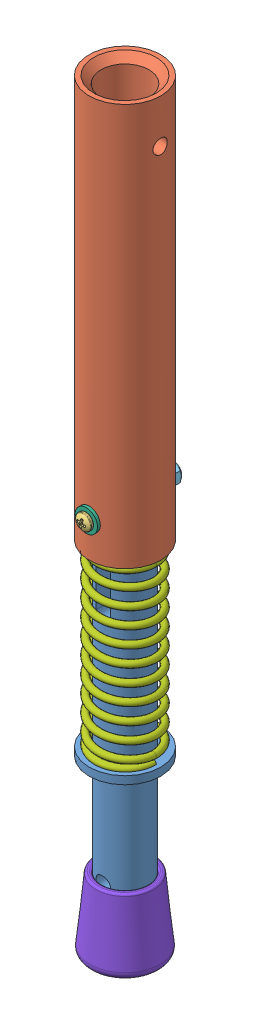
SolidWorks assembly Spoke Subassembly 060815, configuration Default. Lengths in mm.
Overall size (40.39 269.49 40.32).
9 component instances, 8 part files, 18 mates.
Components (placement in the parent):
- Leg Rod Part_new2-1: Leg Rod Part_new2 [Default] at (38.5785 5.0186 -4.9375) size (25.4 190.5 25.4)
- Leg Tube Part_new2-1: Leg Tube Part_new2 [Default] at (38.5785 119.3186 -4.9375) x (0 0 -1) z (1 0 0) size (25.4 142.49 25.4)
- 4 40 Phil Screw2-1: 4 40 Phil Screw2 [91772A116] at (38.5785 132.0186 -22.9715) x (-0.199226 -0.979954 0) z (0 0 1) size (5.56 5.56 34.06)
- Bushing Size 4 1_new2-1: Bushing Size 4 1_new2 [94639A668] at (38.5785 132.0186 -2.3975) size (4.76 4.76 20.32)
- 4 40 Nylon Insert Nut2-1: 4 40 Nylon Insert Nut2 [90631A005] at (38.5785 132.0186 -18.6535) x (1 0 0) z (0 1 0) size (6.35 3.66 7.33)
- Washer Size 4_new2-1: Washer Size 4_new2 [96659A101] at (38.5785 132.0186 7.7625) x (1 0 0) z (0 -1 0) size (7.92 1.02 7.92)
- Washer Size 4_new2-2: Washer Size 4_new2 [96659A101] at (38.5785 132.0186 -17.6375) x (1 0 0) z (0 1 0) size (7.92 1.02 7.92)
- Spring_new2-1: Spring_new2 [9657K254] at (38.5785 119.3186 -4.9375) x (1 0 0) z (0 1 0) size (22.53 22.77 64.66)
- Boot_new2-1: Boot_new2 [Default] at (38.5785 -7.6814 -4.9375) x (0.728126 0 -0.685443) z (0.685443 0 0.728126) size (29.42 25.4 27.68)
Mates (geometry in assembly coordinates):
- Coincident1: coincident aligned: plane of Leg Rod Part_new2-1 through (38.5785 5.0186 -4.9375) normal (1 0 0); plane of Leg Tube Part_new2-1 through (38.5785 119.3186 -4.9375) normal (1 0 0)
- Concentric3: concentric aligned: cylinder of Leg Tube Part_new2-1 through (38.5785 132.0186 7.7625) axis (0 0 -1) radius 2.54; cylinder of 4 40 Phil Screw2-1 through (38.5785 132.0186 -22.9715) axis (0 0 -1) radius 2.7813
- Concentric4: concentric aligned: cylinder of Bushing Size 4 1_new2-1 through (38.5785 132.0186 7.7625) axis (0 0 -1) radius 1.4605; cylinder of 4 40 Phil Screw2-1 through (38.5785 132.0186 -22.9715) axis (0 0 -1) radius 2.7813
- Coincident10: coincident anti-aligned: plane of 4 40 Phil Screw2-1 through (38.5785 132.0186 8.7785) normal (0 0 -1); plane of Washer Size 4_new2-1 through (38.5785 132.0186 8.7785) normal (0 0 1)
- Concentric5: concentric anti-aligned: cylinder of Washer Size 4_new2-1 through (38.5785 132.0186 7.7625) axis (0 0 1) radius 1.5875; cylinder of 4 40 Phil Screw2-1 through (38.5785 132.0186 -22.9715) axis (0 0 -1) radius 2.7813
- Coincident12: coincident anti-aligned: plane of Bushing Size 4 1_new2-1 through (38.5785 132.0186 7.7625) normal (0 0 1); plane of Washer Size 4_new2-1 through (38.5785 132.0186 7.7625) normal (0 0 -1)
- Tangent2: tangent anti-aligned: plane of Washer Size 4_new2-1 through (38.5785 132.0186 7.7625) normal (0 0 -1); cylinder of Leg Tube Part_new2-1 through (38.5785 119.3186 -4.9375) axis (0 1 0) radius 12.7
- Coincident13: coincident anti-aligned: circle of 4 40 Nylon Insert Nut2-1; plane of Washer Size 4_new2-2 through (38.5785 132.0186 -18.6535) normal (0 0 -1)
- Concentric6: concentric aligned: circle of 4 40 Nylon Insert Nut2-1; cylinder of Washer Size 4_new2-2 through (38.5785 132.0186 -17.6375) axis (0 0 -1) radius 1.5875
- Concentric7: concentric aligned: cylinder of Washer Size 4_new2-2 through (38.5785 132.0186 -17.6375) axis (0 0 -1) radius 1.5875; cylinder of 4 40 Phil Screw2-1 through (38.5785 132.0186 -22.9715) axis (0 0 -1) radius 2.7813
- Tangent3: tangent anti-aligned: plane of Washer Size 4_new2-2 through (38.5785 132.0186 -17.6375) normal (0 0 1); cylinder of Leg Tube Part_new2-1 through (38.5785 119.3186 -4.9375) axis (0 1 0) radius 12.7
- Coincident14: coincident anti-aligned: plane of Leg Tube Part_new2-1 through (38.5785 119.3186 -4.9375) normal (0 -1 0); plane of Spring_new2-1 through (38.5785 119.3186 -4.9375) normal (0 1 0)
- Coincident15: coincident anti-aligned: plane of Leg Rod Part_new2-1 through (38.5785 5.0186 -4.9375) normal (0 -1 0); plane of Boot_new2-1 through (38.5785 5.0186 -4.9375) normal (0 1 0)
- Concentric8: concentric anti-aligned: cylinder of Leg Rod Part_new2-1 through (38.5785 195.5186 -4.9375) axis (0 -1 0) radius 8.128; cylinder of Boot_new2-1 through (38.5785 5.0186 -4.9375) axis (0 1 0) radius 8.128
- LimitDistance1: limit distance = 63.5 mm anti-aligned: plane of Leg Tube Part_new2-1 through (38.5785 119.3186 -4.9375) normal (0 -1 0); plane of Leg Rod Part_new2-1 through (38.5785 55.8186 -4.9375) normal (0 1 0)
- Concentric9: concentric aligned: cylinder of Leg Rod Part_new2-1 through (38.5785 195.5186 -4.9375) axis (0 -1 0) radius 8.128; cylinder of Leg Tube Part_new2-1 through (38.5785 285.8796 -4.9375) axis (0 -1 0) radius 8.509
- Coincident16: coincident aligned: plane of Leg Tube Part_new2-1 through (38.5785 119.3186 -4.9375) normal (0 0 -1); plane of Spring_new2-1 through (38.5785 119.3186 -4.9375) normal (0 0 -1)
- Coincident19: coincident aligned: plane of Leg Tube Part_new2-1 through (38.5785 119.3186 -4.9375) normal (1 0 0); plane of Spring_new2-1
